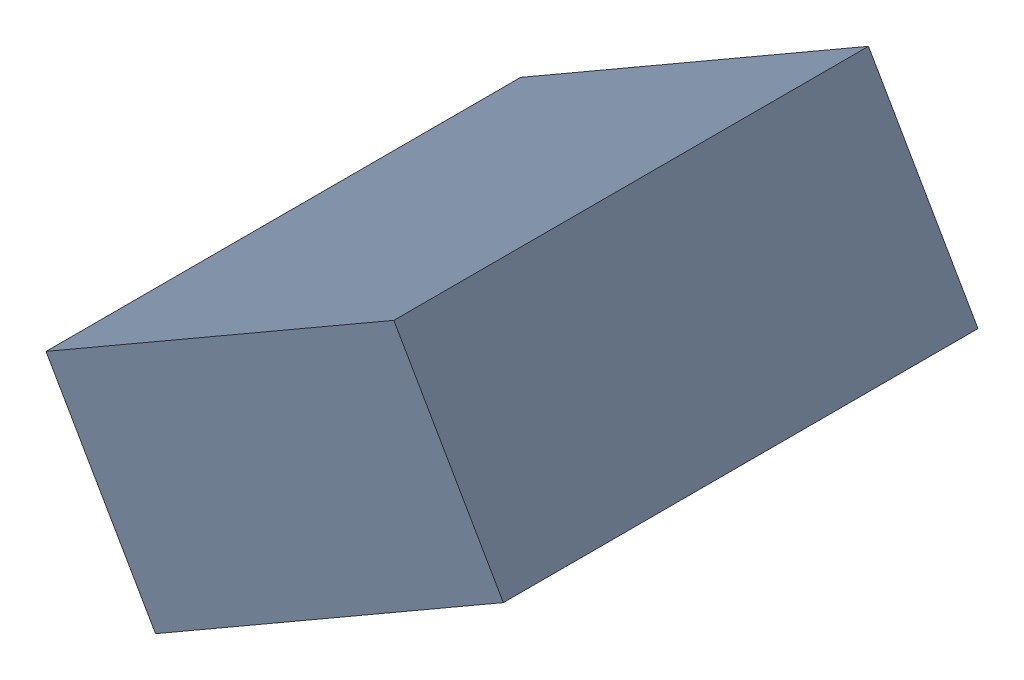
SolidWorks assembly C21_TDA2, configuration Standard. Lengths in mm.
Overall size (1.25 1.07 1.3).
2 component instances, 1 part files, 0 mates.
Components (placement in the parent):
- 885542920-1: 885542920 [Standard] at (39.4826 31.4092 0) size (1.25 1.07 1.3)
  - Extruded_24-1: Extruded_24 [Standard] at origin size (1.25 1.07 1.3)
